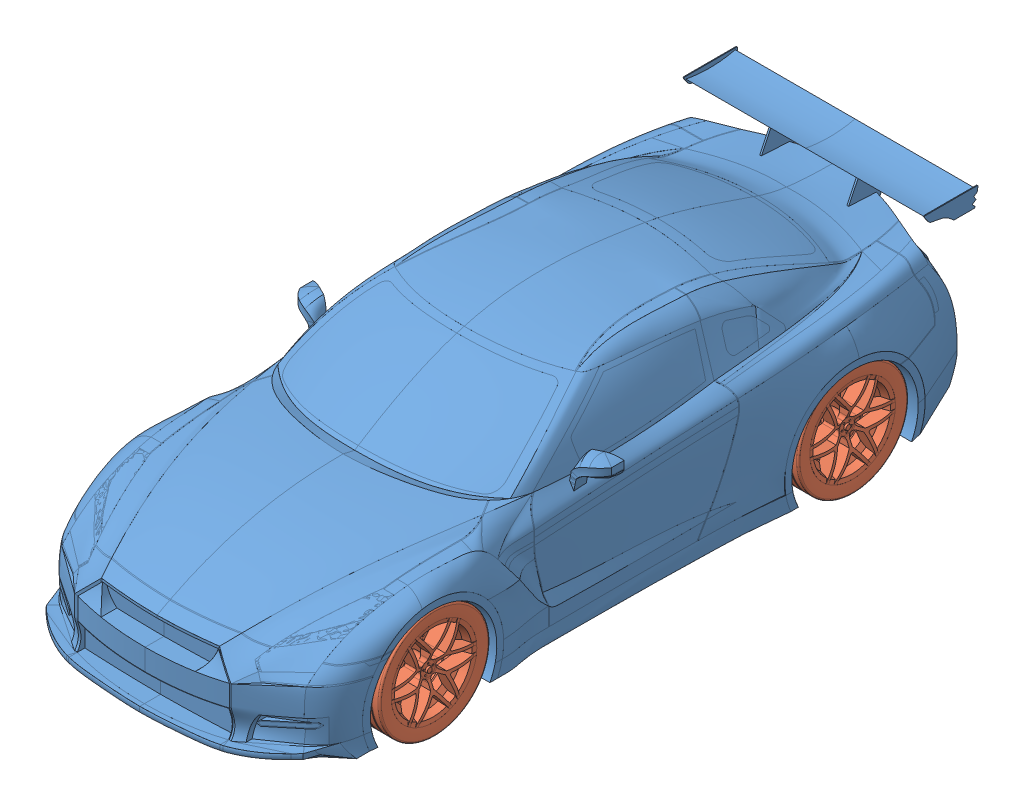
SolidWorks assembly Nissan GTR_Full, configuration Default. Lengths in mm.
Overall size (364.14 247.46 840.09).
5 component instances, 2 part files, 4 mates.
Components (placement in the parent):
- Nissan GTR-1: Nissan GTR [Default] at (196.2596 329.6421 1127.7852) size (364.14 247.46 840.09)
- Nissan GTR_Wheel-1: Nissan GTR_Wheel [Default] at (337.6214 333.3758 947.8807) size (63.07 129 129)
- Nissan GTR_Wheel-2: Nissan GTR_Wheel [Default] at (336.5383 462.3945 457.3611) x (1 0 0) z (0 0 -1) size (63.07 129 129)
- Nissan GTR_Wheel-3: Nissan GTR_Wheel [Default] at (54.8978 462.3758 947.8807) x (-1 0 0) z (0 0 1) size (63.07 129 129)
- Nissan GTR_Wheel-4: Nissan GTR_Wheel [Default] at (55.9809 333.3945 457.3611) x (-1 0 0) z (0 0 -1) size (63.07 129 129)
Mates (geometry in assembly coordinates):
- Concentric5: concentric anti-aligned: circle of Nissan GTR-1; circle of Nissan GTR_Wheel-1
- Coincident1: coincident anti-aligned: plane of Nissan GTR-1 through (308.2596 329.6421 1127.7852) normal (1 0 0); circle of Nissan GTR_Wheel-1
- Concentric6: concentric anti-aligned: circle of Nissan GTR-1; circle of Nissan GTR_Wheel-2
- Coincident2: coincident anti-aligned: plane of Nissan GTR-1 through (306.2596 329.6421 1127.7852) normal (1 0 0); plane of Nissan GTR_Wheel-2 through (306.2596 397.8945 457.3611) normal (-1 0 0)
